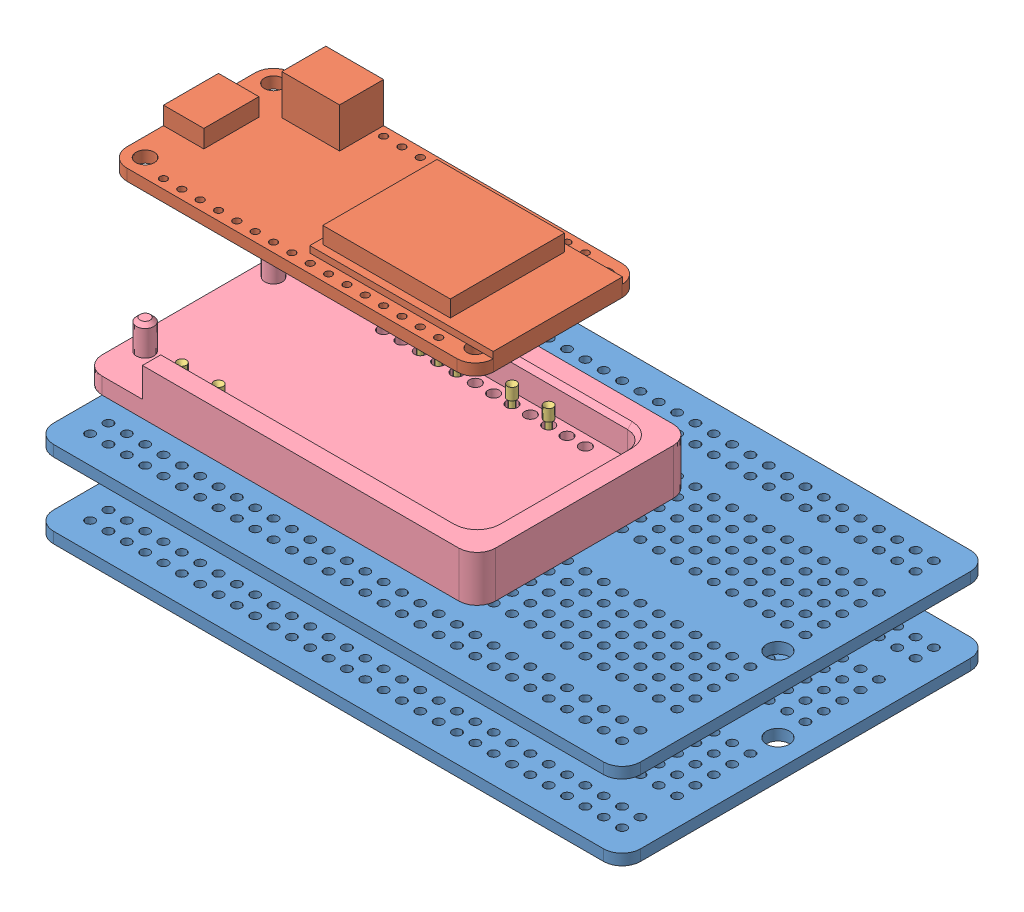
SolidWorks assembly Programming jig, configuration Default. Lengths in mm.
Overall size (83.82 42.99 50.8).
11 component instances, 4 part files, 22 mates.
Components (placement in the parent):
- Perma-proto-1: Perma-proto [Default] at (-10.7141 39.8957 89.2025) size (81.28 1.52 50.8)
- HUZZAH32-1: HUZZAH32 [Default] at (37.5459 65.3464 53.6425) x (-1 0 0) z (0 0 -1) size (50.8 7.12 22.86)
- Pogo pin cup-1: Pogo pin cup [Default] at (-4.3641 29.4817 75.2325) size (1.27 16.66 1.27)
- Pogo pin cup-2: Pogo pin cup [Default] at (0.7159 29.4817 75.2325) size (1.27 16.66 1.27)
- Pogo pin cup-3: Pogo pin cup [Default] at (8.3359 29.4817 54.9125) size (1.27 16.66 1.27)
- Pogo pin cup-4: Pogo pin cup [Default] at (10.8759 29.4817 54.9125) size (1.27 16.66 1.27)
- Pogo pin cup-5: Pogo pin cup [Default] at (13.4159 29.4817 54.9125) size (1.27 16.66 1.27)
- Pogo pin cup-6: Pogo pin cup [Default] at (21.0359 29.4817 54.9125) size (1.27 16.66 1.27)
- Pogo pin cup-7: Pogo pin cup [Default] at (26.1159 29.4817 54.9125) size (1.27 16.66 1.27)
- Perma-proto-2: Perma-proto [Default] at (-10.7141 29.4817 89.2025) size (81.28 1.52 50.8)
- Part4^Programming jig-1: Part4^Programming jig [Default] at (-13.2541 41.4197 79.9315) size (54.48 6.35 29.72) (virtual)
Mates (geometry in assembly coordinates):
- Concentric1: concentric anti-aligned: cylinder of Perma-proto-1 through (-4.3641 41.4197 75.2325) axis (0 -1 0) radius 0.635; cylinder of Pogo pin cup-1 through (-4.3641 47.7673 75.2325) axis (0 1 0) radius 0.508
- Concentric2: concentric anti-aligned: cylinder of Perma-proto-1 through (0.7159 41.4197 75.2325) axis (0 -1 0) radius 0.635; cylinder of Pogo pin cup-2 through (0.7159 47.7673 75.2325) axis (0 1 0) radius 0.508
- Concentric3: concentric anti-aligned: cylinder of Perma-proto-1 through (8.3359 41.4197 54.9125) axis (0 -1 0) radius 0.635; cylinder of Pogo pin cup-3 through (8.3359 47.7673 54.9125) axis (0 1 0) radius 0.508
- Concentric4: concentric anti-aligned: cylinder of Perma-proto-1 through (10.8759 41.4197 54.9125) axis (0 -1 0) radius 0.635; cylinder of Pogo pin cup-4 through (10.8759 47.7673 54.9125) axis (0 1 0) radius 0.508
- Concentric5: concentric anti-aligned: cylinder of Perma-proto-1 through (13.4159 41.4197 54.9125) axis (0 -1 0) radius 0.635; cylinder of Pogo pin cup-5 through (13.4159 47.7673 54.9125) axis (0 1 0) radius 0.508
- Concentric6: concentric anti-aligned: cylinder of Perma-proto-1 through (21.0359 41.4197 54.9125) axis (0 -1 0) radius 0.635; cylinder of Pogo pin cup-6 through (21.0359 47.7673 54.9125) axis (0 1 0) radius 0.508
- Concentric7: concentric anti-aligned: cylinder of Perma-proto-1 through (26.1159 41.4197 54.9125) axis (0 -1 0) radius 0.635; cylinder of Pogo pin cup-7 through (26.1159 47.7673 54.9125) axis (0 1 0) radius 0.508
- Concentric10: concentric aligned: cylinder of Perma-proto-1 through (-6.9041 41.4197 63.8025) axis (0 -1 0) radius 1.5875; cylinder of Perma-proto-2 through (-6.9041 31.0057 63.8025) axis (0 -1 0) radius 1.5875
- Concentric11: concentric aligned: cylinder of Perma-proto-1 through (66.7559 41.4197 63.8025) axis (0 -1 0) radius 1.5875; cylinder of Perma-proto-2 through (66.7559 31.0057 63.8025) axis (0 -1 0) radius 1.5875
- Distance1: distance = 8.89 mm anti-aligned: plane of Perma-proto-2 through (68.0259 31.0057 40.9425) normal (0 1 0); plane of Perma-proto-1 through (68.0259 39.8957 40.9425) normal (0 -1 0)
- Coincident3: coincident aligned: plane of Pogo pin cup-1 through (-4.3641 29.4817 75.2325) normal (0 -1 0); plane of assembly through (0 29.4817 0) normal (0 -1 0)
- Coincident4: coincident aligned: plane of assembly through (0 29.4817 0) normal (0 -1 0); plane of Pogo pin cup-3 through (8.3359 29.4817 54.9125) normal (0 -1 0)
- Coincident5: coincident aligned: plane of Pogo pin cup-2 through (0.7159 29.4817 75.2325) normal (0 -1 0); plane of assembly through (0 29.4817 0) normal (0 -1 0)
- Coincident6: coincident aligned: plane of Pogo pin cup-4 through (10.8759 29.4817 54.9125) normal (0 -1 0); plane of assembly through (0 29.4817 0) normal (0 -1 0)
- Coincident7: coincident aligned: plane of Pogo pin cup-5 through (13.4159 29.4817 54.9125) normal (0 -1 0); plane of assembly through (0 29.4817 0) normal (0 -1 0)
- Coincident8: coincident aligned: plane of Pogo pin cup-6 through (21.0359 29.4817 54.9125) normal (0 -1 0); plane of assembly through (0 29.4817 0) normal (0 -1 0)
- Coincident9: coincident aligned: plane of Pogo pin cup-7 through (26.1159 29.4817 54.9125) normal (0 -1 0); plane of assembly through (0 29.4817 0) normal (0 -1 0)
- Concentric12: concentric aligned: cylinder of Perma-proto-1 through (-6.9041 41.4197 75.2325) axis (0 -1 0) radius 0.635; cylinder of HUZZAH32-1 through (-6.9041 66.9339 75.2325) axis (0 -1 0) radius 0.508
- Concentric13: concentric aligned: cylinder of Perma-proto-1 through (3.2559 41.4197 54.9125) axis (0 -1 0) radius 0.635; cylinder of HUZZAH32-1 through (3.2559 66.9339 54.9125) axis (0 -1 0) radius 0.508
- Concentric15: concentric aligned: cylinder of Perma-proto-1 through (-6.9041 41.4197 75.2325) axis (0 -1 0) radius 0.635; cylinder of Part4^Programming jig-1 through (-6.9041 43.7057 75.2325) axis (0 -1 0) radius 0.7937
- Coincident10: coincident anti-aligned: plane of Perma-proto-1 through (68.0259 41.4197 40.9425) normal (0 1 0); plane of Part4^Programming jig-1 through (-13.2541 41.4197 79.9315) normal (0 -1 0)
- Concentric16: concentric aligned: cylinder of Perma-proto-1 through (3.2559 41.4197 54.9125) axis (0 -1 0) radius 0.635; cylinder of Part4^Programming jig-1 through (3.2559 43.7057 54.9125) axis (0 -1 0) radius 0.7937
